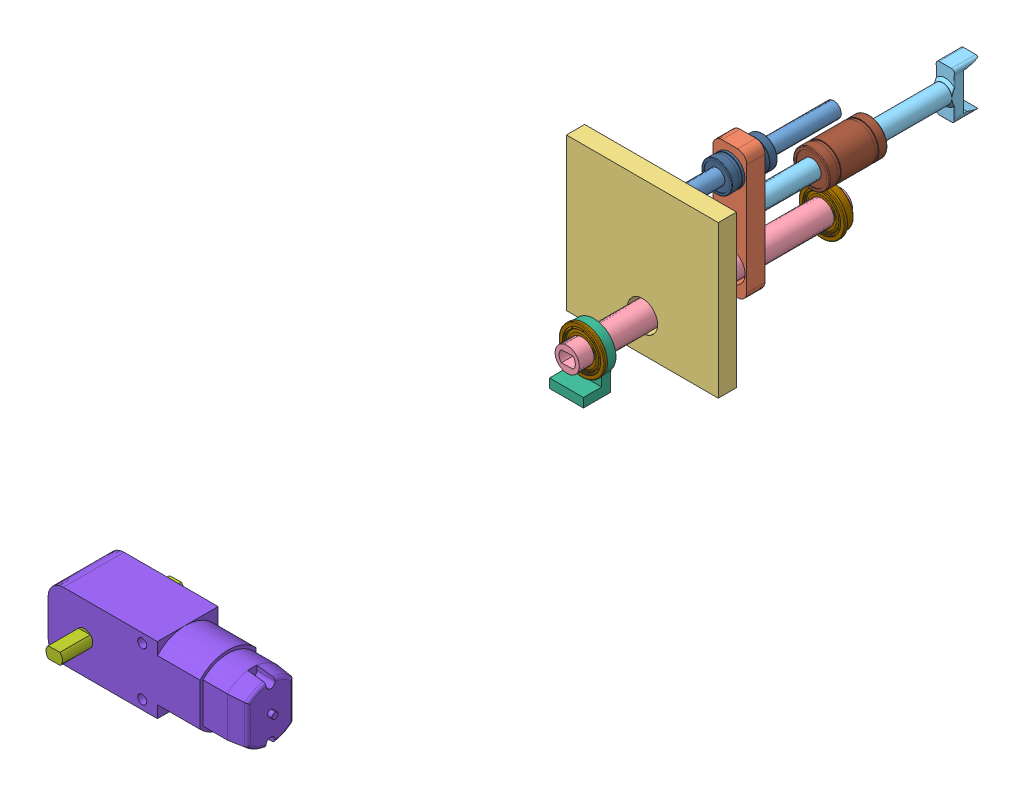
SolidWorks assembly 1111, configuration Default. Lengths in mm.
Overall size (78.55 50.1 301.56).
19 component instances, 17 part files, 23 mates.
Components (placement in the parent):
- Part1-1: Part1 [Default] at (143.7185 269.3433 346.6568) x (0 0 -1) z (0 -1 0) size (450 350 75) (hidden)
- Assem1-2: Assem1 [Default] at (157.6708 270.9364 572.297) x (-0.999437 0 -0.033541) z (0.033541 0 -0.999437) size (53.6 85 53.71) (hidden)
- Part5-1: Part5 [Default] at (173.2213 349.3073 532.9764) x (0.001541 0.998944 -0.045926) z (-0.999437 0 -0.033541) size (25.24 16.44 60) (hidden)
- Part1^1111-2: Part1^1111 [Default] at (168.7185 244.3433 439.2535) x (0 0 1) z (-1 0 0) size (10 50 50) (hidden, virtual)
- Part2^1111-1: Part2^1111 [Default] at origin (virtual)
- Part3^1111-1: Part3^1111 [Default] at (124.1501 232.1809 441.2239) x (0.026267 -0.999655 0) z (0 0 1) size (5 5 60) (virtual)
- Part4^1111-1: Part4^1111 [Default] at (167.3132 245.7727 469.4615) x (0.997978 0.063564 0) z (0 0 1) size (13.49 42.81 6) (virtual)
- Part5^1111-1: Part5^1111 [Default] at (168.7185 244.4474 504.2535) size (50 50.1 6) (virtual)
- Part6^1111-1: Part6^1111 [Default] at (0 0 421.6568) (virtual)
- Part7^1111-1: Part7^1111 [Default] at (168.7697 247.1305 514.0598) size (8 8 90) (virtual)
- Partrod33-2: Partrod33 [Default] at (143.7185 244.3433 469.4615) x (-1 0 0) z (0 0 -1) size (6.27 15.36 73)
- Part8^1111-1: Part8^1111 [Default] at (168.7185 244.4474 520.2535) size (14.5 18.25 9) (virtual)
- Motorreductor-1: Motorreductor [Predeterminado] at (156.7697 230.3433 678.0165) size (71 22 40)
  - Eje-1: Eje [Predeterminado] at (-13 0 0) x (0.999574 0.029171 0) z (0.029171 -0.999574 0) size (5.4 40 5.4)
  - Motor sin eje-1: Motor sin eje [Predeterminado] at origin size (71 22 20)
- Ball Bearing F695ZZ-1: Ball Bearing F695ZZ [Défaut] at (143.7697 230.3433 522.3098) x (0.994196 -0.107586 0) z (0 0 1) size (15 15 4.16)
- Ball Bearing F695ZZ-2: Ball Bearing F695ZZ [Défaut] at (143.7697 230.3433 443.2535) size (15 15 4.16)
- ball_bearing_lm5uu-1: ball_bearing_lm5uu [Default] at (143.7185 257.7037 472.2457) x (0 0 -1) z (0.999661 0.026019 0) size (15 10 10)
- ball_bearing_lm6uu-1: ball_bearing_lm6uu [Default] at (143.7185 244.3433 439.0853) x (0 0 -1) z (0.87376 -0.486357 0) size (19 12 12)
Mates (geometry in assembly coordinates):
- Concentric1: concentric anti-aligned: circle of Part1-1; circle of Assem1-2
- Coincident2: coincident anti-aligned: plane of Part1-1 through (143.7185 289.3433 346.6568) normal (0 1 0); plane of Assem1-2 through (143.7185 289.3433 525.0443) normal (0 -1 0)
- Concentric2: concentric aligned: circle of Assem1-2; circle of Part5-1
- Distance1: distance = 0 mm anti-aligned: plane of Part5-1 through (118.4994 348.324 523.7655) normal (0.999437 0 0.033541); plane of Assem1-2 through (118.8232 323.2755 514.117) normal (-0.999437 0 -0.033541)
- Coincident22: coincident anti-aligned: plane of Part1-1 through (143.7185 219.3433 346.6568) normal (0 1 0); plane of Part1^1111-2 through (118.7185 219.3433 434.2535) normal (0 -1 0)
- Coincident23: coincident anti-aligned: plane of Part1-1 through (168.7185 269.3433 346.6568) normal (-1 0 0); plane of Part1^1111-2 through (168.7185 244.3433 439.2535) normal (1 0 0)
- Coincident24: coincident anti-aligned: plane of Part1-1 through (143.7185 219.3433 346.6568) normal (0 1 0); plane of Part5^1111-1 through (118.7185 219.3433 498.2535) normal (0 -1 0)
- Coincident25: coincident aligned: plane of Part1^1111-2 through (118.7185 244.3433 439.2535) normal (-1 0 0); plane of Part5^1111-1 through (118.7185 269.4474 498.2535) normal (-1 0 0)
- Concentric3: concentric aligned: circle of Part5^1111-1; circle of Part7^1111-1
- Concentric6: concentric aligned: circle of Part1^1111-2; circle of Partrod33-2
- Coincident29: coincident anti-aligned: plane of Part4^1111-1 through (167.3132 245.7727 469.4615) normal (0 0 -1); plane of Partrod33-2 through (143.7185 244.3433 469.4615) normal (0 0 1)
- Coincident33: coincident aligned: plane of Part5^1111-1 through (118.7185 219.3433 498.2535) normal (0 -1 0); plane of Part8^1111-1 through (138.1295 219.3433 523.2535) normal (0 -1 0)
- Coincident34: coincident aligned: plane of Part5^1111-1 through (118.7185 219.3433 498.2535) normal (0 -1 0); plane of Motorreductor-1/Motor sin eje-1 through (156.7697 219.3433 678.0165) normal (0 -1 0)
- Coincident35: coincident anti-aligned: plane of Part7^1111-1 through (141.75 232.1351 519.0598) normal (0.029171 -0.999574 0); plane of Motorreductor-1/Eje-1 through (145.6815 232.2498 658.0165) normal (-0.029171 0.999574 0)
- Concentric10: concentric aligned: circle of Motorreductor-1/Eje-1; circle of Ball Bearing F695ZZ-1
- Concentric11: concentric aligned: circle of Part8^1111-1; circle of Ball Bearing F695ZZ-1
- Concentric12: concentric anti-aligned: circle of Part7^1111-1; circle of Ball Bearing F695ZZ-2
- Coincident37: coincident anti-aligned: plane of Part1^1111-2 through (118.7185 219.3433 444.2535) normal (0 0 1); plane of Ball Bearing F695ZZ-2 through (143.7697 230.3433 444.2535) normal (0 0 -1)
- Concentric13: concentric aligned: circle of Part4^1111-1; circle of Part7^1111-1
- Parallel3: parallel aligned: plane of Part1^1111-2 through (118.7185 219.3433 434.2535) normal (0 -1 0); plane of Part4^1111-1 through (167.3132 222.3433 475.4615) normal (0 -1 0)
- Concentric16: concentric aligned: circle of Part4^1111-1; circle of ball_bearing_lm5uu-1
- Concentric17: concentric aligned: circle of Part3^1111-1; circle of ball_bearing_lm5uu-1
- Concentric18: concentric anti-aligned: circle of Partrod33-2; circle of ball_bearing_lm6uu-1
